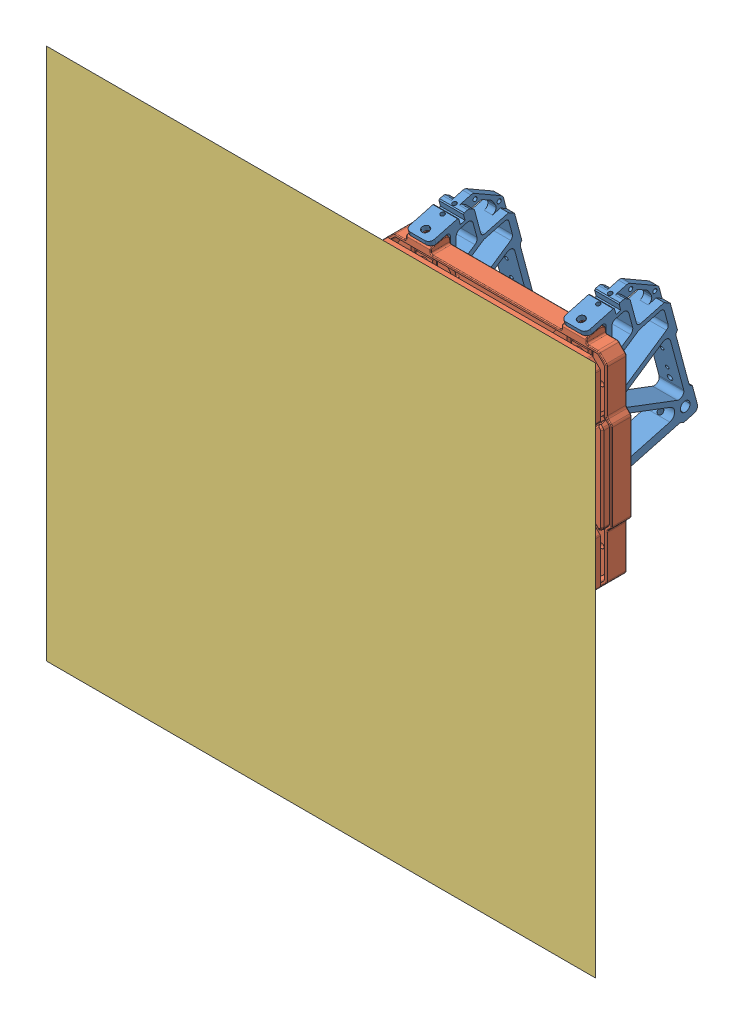
SolidWorks assembly 小装甲(WithSupport), configuration 默认. Lengths in mm.
Overall size (335 261.4 174.83).
4 component instances, 3 part files, 10 mates.
Components (placement in the parent):
- RM2019裁判系统支撑架AH02-1: RM2019裁判系统支撑架AH02 [默认] at (-15.033 -31.1753 152.6103) size (15 130.97 68.39)
- RM2019裁判系统装甲模块AM02-1: RM2019裁判系统装甲模块AM02 [默认] at (-107.5374 -73.9899 179.5172) x (0 0 1) z (-1 0 0) size (19 129.97 141)
- RM2019裁判系统支撑架AH02-2: RM2019裁判系统支撑架AH02 [默认] at (-110.033 -31.1753 152.6103) size (15 130.97 68.39)
- Area-1: Area [默认] at (-107.5374 -73.9899 171.6103) size (335 261.4 100)
Mates (geometry in assembly coordinates):
- 重合1: coincident: plane of assembly; plane of assembly; plane of RM2019裁判系统支撑架AH02-1 through (-7.533 58.8247 152.6103) normal (0 0 1); plane of RM2019裁判系统装甲模块AM02-1 through (-62.533 -10.0287 152.6103) normal (0 0 -1)
- 重合2: coincident: plane of assembly; plane of assembly; plane of RM2019裁判系统装甲模块AM02-1 through (-62.533 -10.0287 152.6103) normal (0 0 -1); plane of RM2019裁判系统支撑架AH02-2 through (-102.533 58.8247 152.6103) normal (0 0 1)
- 重合3: coincident: plane of assembly; plane of assembly; plane of RM2019裁判系统装甲模块AM02-1 through (-102.533 58.6867 152.6103) normal (0 0.965926 0.258819); plane of RM2019裁判系统支撑架AH02-2 through (-131.6523 58.6867 152.6103) normal (0 -0.965926 -0.258819)
- 重合4: coincident: plane of assembly; plane of assembly; plane of RM2019裁判系统支撑架AH02-1 through (-36.6523 58.6867 152.6103) normal (0 -0.965926 -0.258819); plane of RM2019裁判系统装甲模块AM02-1 through (-102.533 58.6867 152.6103) normal (0 0.965926 0.258819)
- 重合5: coincident: plane of assembly; plane of assembly; plane of RM2019裁判系统装甲模块AM02-1 through (-117.533 -10.0287 152.6103) normal (-1 0 0); plane of RM2019裁判系统支撑架AH02-2 through (-117.533 -31.1753 152.6103) normal (-1 0 0)
- 重合6: coincident: plane of assembly; plane of assembly; plane of RM2019裁判系统支撑架AH02-1 through (-22.533 -31.1753 152.6103) normal (-1 0 0); plane of RM2019裁判系统装甲模块AM02-1 through (-22.533 -10.0287 152.6103) normal (-1 0 0)
- 在位1: in place: plane of RM2019裁判系统装甲模块AM02-1 through (-62.533 -10.0937 171.6103) normal (0 0 1); plane of ? through (0 0 171.6103) normal (0 0 1); moOrthogonalPlaneRef_w of RM2019裁判系统装甲模块AM02-1 through (-62.533 -10.0937 171.6103) normal (0 0 1); plane of ? through (0 0 171.6103) normal (0 1 0); plane of RM2019裁判系统装甲模块AM02-1 through (-62.533 -10.0937 171.6103) normal (0 0 1); plane of ? through (0 0 171.6103) normal (1 0 0); plane of RM2019裁判系统装甲模块AM02-1 through (-62.533 -10.0937 171.6103) normal (0 0 1); unknown of Area-1
- 重合7: coincident: plane of assembly; plane of assembly; plane of RM2019裁判系统装甲模块AM02-1; plane of Area-1
- 重合8: coincident: plane of assembly; plane of assembly; moOrthogonalPlaneRef_w of RM2019裁判系统装甲模块AM02-1 through (-107.5374 -73.9899 171.6103) normal (0 1 0); plane of Area-1 through (-107.5374 -73.9899 171.6103) normal (0 1 0)
- 重合9: coincident: plane of assembly; plane of assembly; moOrthogonalPlaneRef_w of RM2019裁判系统装甲模块AM02-1 through (-107.5374 -73.9899 171.6103) normal (-1 0 0); plane of Area-1 through (-107.5374 -73.9899 171.6103) normal (1 0 0)
